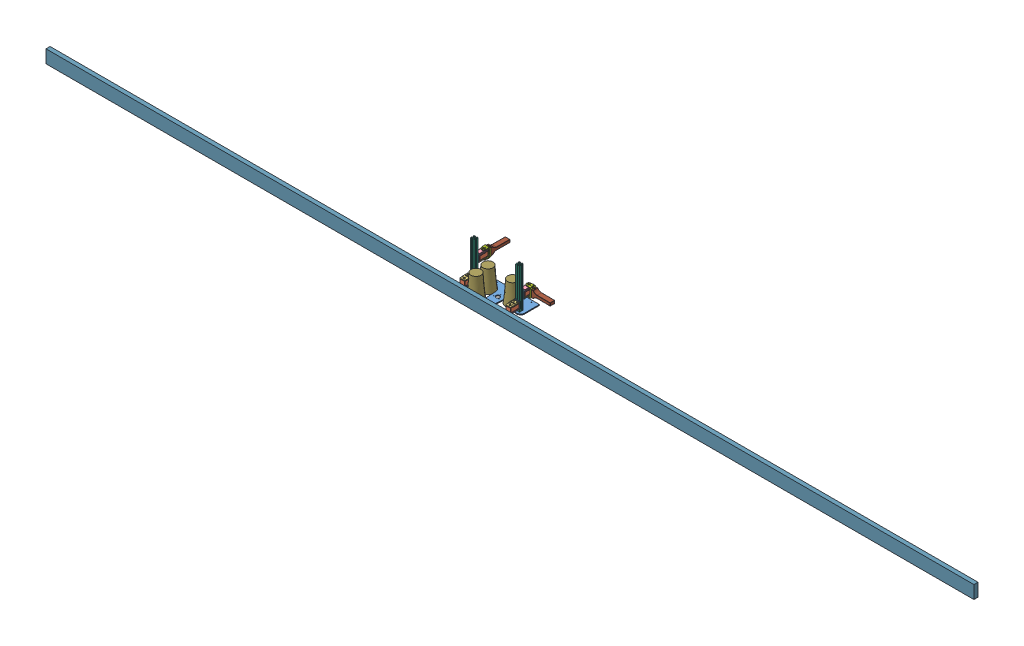
SolidWorks assembly assemblage plaque v3.0 23_12, configuration Défaut. Lengths in mm.
Overall size (5000 224.14 298.64).
45 component instances, 15 part files, 59 mates.
Components (placement in the parent):
- Plaque v1.1-1: Plaque v1.1 [Défaut] at (-264.5937 254.2279 63.4692) size (298 4.6 145)
- assemblage AX-12A avec horn F3-1: assemblage AX-12A avec horn F3 [Default] at (21.408 292.0771 45.8254) x (0.999019 0 -0.044277) z (0 1 0) size (31 53.5 38)
  - badan servo-1: badan servo [Default] at (-24.946 29.9749 -7.2009) size (25 48 22)
  - Belakang-1: Belakang [Default] at (-24.946 29.9749 14.7991) size (31 49.5 8.5)
  - depan servo-1: depan servo [Default] at (0.054 29.9749 -7.2009) x (-1 0 0) z (0 0 -1) size (31 49.5 8.5)
  - F3-1: F3 [Default] at (-12.446 36.9749 3.7991) x (-1 0 0) z (0 0 1) size (25 9 38)
- ProfileSup-1: ProfileSup [Défaut] at (6.4063 258.8279 -0.5308) x (0.999019 0 -0.044277) z (0.044277 0 0.999019) size (20 217.4 20)
- F3-1: F3 [Default] at (7.337 295.8763 9.4378) x (-0.999019 0 0.044277) z (0 1 0) size (25 9 38)
- FP04-F2-1: FP04-F2 [Default] at (5.3068 329.3416 -52.5331) x (0 1 0) z (0.999979 0 0.00642) size (48.81 25 37)
- F3-2: F3 [Default] at (7.1664 330.3416 -10.5743) x (-0.999019 0 0.044277) z (0 -1 0) size (25 9 38)
- assemblage AX-12A avec horn F3-2: assemblage AX-12A avec horn F3 [Default] at (17.9631 334.1408 -48.064) x (0.999019 0 -0.044277) z (0 -1 0) size (31 53.5 38)
  - badan servo-1: badan servo [Default] at (-24.946 29.9749 -7.2009) size (25 48 22)
  - Belakang-1: Belakang [Default] at (-24.946 29.9749 14.7991) size (31 49.5 8.5)
  - depan servo-1: depan servo [Default] at (0.054 29.9749 -7.2009) x (-1 0 0) z (0 0 -1) size (31 49.5 8.5)
  - F3-1: F3 [Default] at (-12.446 36.9749 3.7991) x (-1 0 0) z (0 0 1) size (25 9 38)
- horn-1: horn [Default] at (5.3068 346.3416 -52.5331) x (-0.999979 0 -0.00642) z (0.00642 0 -0.999979) size (20.6 4 20.6)
- horn-2: horn [Default] at (9.1967 279.8763 51.3966) x (-0.940361 0 -0.340179) z (-0.340179 0 0.940361) size (20.6 4 20.6)
- FR04-BU-1: FR04-BU [Default] at (5.3068 310.9416 -52.5331) x (1 0 0) z (0 0 -1) size (10 7.1 10)
- FR04-WA-1: FR04-WA [Default] at (5.3068 310.4416 -52.5331) x (0.9995 0 0.031614) z (-0.031614 0 0.9995) size (12 1.9 12)
- baguette v3.0 23_12-1: baguette v3.0 23_12 [Défaut] at (41.306 310.3416 -52.302) x (0.00642 0 -0.999979) z (0.999979 0 0.00642) size (25 38 102)
- ProfileSup-2: ProfileSup [Défaut] at (-237.5937 258.8279 -0.5308) size (20 217.4 20)
- AX12_F3-1: AX12_F3 [Défaut] at (-319.3447 268.4285 33.1229) x (1 0 0) z (0 1 0) size (31 53.5 38)
  - assemblage AX-12A avec horn F3-1: assemblage AX-12A avec horn F3 [Default] at (94.197 -13.3212 25.6002) size (31 53.5 38)
    - badan servo-1: badan servo [Default] at (-24.946 29.9749 -7.2009) size (25 48 22)
    - Belakang-1: Belakang [Default] at (-24.946 29.9749 14.7991) size (31 49.5 8.5)
    - depan servo-1: depan servo [Default] at (0.054 29.9749 -7.2009) x (-1 0 0) z (0 0 -1) size (31 49.5 8.5)
    - F3-1: F3 [Default] at (-12.446 36.9749 3.7991) x (-1 0 0) z (0 0 1) size (25 9 38)
  - F3-1: F3 [Default] at (81.751 23.6537 29.3994) x (-1 0 0) z (0 0 1) size (25 9 38)
- horn-3: horn [Default] at (-237.5937 281.8279 51.4692) x (0.00254 0 0.999997) z (0.999997 0 -0.00254) size (20.6 4 20.6)
- AX12_F3-2: AX12_F3 [Défaut] at (-319.3447 407.2273 -34.1845) x (1 0 0) z (0 -1 0) size (31 53.5 38)
  - assemblage AX-12A avec horn F3-1: assemblage AX-12A avec horn F3 [Default] at (94.197 -13.3212 25.6002) size (31 53.5 38)
    - badan servo-1: badan servo [Default] at (-24.946 29.9749 -7.2009) size (25 48 22)
    - Belakang-1: Belakang [Default] at (-24.946 29.9749 14.7991) size (31 49.5 8.5)
    - depan servo-1: depan servo [Default] at (0.054 29.9749 -7.2009) x (-1 0 0) z (0 0 -1) size (31 49.5 8.5)
    - F3-1: F3 [Default] at (-12.446 36.9749 3.7991) x (-1 0 0) z (0 0 1) size (25 9 38)
  - F3-1: F3 [Default] at (81.751 23.6537 29.3994) x (-1 0 0) z (0 0 1) size (25 9 38)
- horn-4: horn [Default] at (-237.5937 393.8279 -52.5308) x (0.00418 0 -0.999991) z (0.999991 0 0.00418) size (20.6 4 20.6)
- FP04-F2-2: FP04-F2 [Default] at (-237.5937 376.8279 -52.5308) x (0 -1 0) z (0.00418 0 -0.999991) size (48.81 25 37)
- baguette v3.0 23_12-2: baguette v3.0 23_12 [Défaut] at (-237.4432 357.8279 -88.5305) x (-0.999991 0 -0.00418) z (0.00418 0 -0.999991) size (25 38 102)
- Goblet_moche-1: Goblet_moche [Défaut] at (-181.3106 254.2279 -18.5717) x (0.923103 0 -0.384552) z (0 1 0) size (85.92 80.5 113.85)
- Goblet_moche-2: Goblet_moche [Défaut] at (-50.1575 254.2279 -20.3567) x (1 0 0) z (0 1 0) size (85.92 80.5 113.85)
- Goblet_moche-3: Goblet_moche [Défaut] at (-173.7307 258.8279 53.3751) x (0.805273 0 -0.592904) z (0 1 0) size (85.92 80.5 113.85)
- GrappinGauche VLED - v3.0 23_12-1: GrappinGauche VLED - v3.0 23_12 [Défaut] at (9.1967 286.8763 51.3966) x (-0.940361 0 -0.340179) z (0 -1 0) size (30.38 51.24 11)
- bordureTable_moche-1: bordureTable_moche [Défaut] at (2573.9862 322.0883 96.0579) x (0 -1 0) z (-1 0 0) size (70 22 5000)
- Flipper bras v1.0-1: Flipper bras v1.0 [Défaut] at (-237.5937 277.8279 51.4692) x (-0.999997 0 0.00254) z (0 -1 0) size (24 54.53 11)
Mates (geometry in assembly coordinates):
- Coïncidente1: coincident: circle of Plaque v1.1-1; circle of ProfileSup-1
- Coïncidente2: coincident: plane of ProfileSup-1 through (16.8393 508.8279 9.0166) normal (0.044277 0 0.999019); plane of F3-1 through (20.3243 313.5563 8.8622) normal (-0.044277 0 -0.999019)
- Coïncidente3: coincident: plane of assemblage AX-12A avec horn F3-1/Belakang-1 through (-3.7975 311.8763 17.9391) normal (0 1 0); plane of F3-1 through (-5.3737 311.8763 13.905) normal (0 -1 0)
- Coaxiale3: concentric: cylinder of assemblage AX-12A avec horn F3-1/Belakang-1 through (-0.4116 306.8763 15.2866) axis (0 1 0) radius 1; cylinder of F3-1 through (-0.4116 311.8763 15.2866) axis (0 1 0) radius 1.05
- Coaxiale4: concentric: circle of assemblage AX-12A avec horn F3-1/Belakang-1; cylinder of F3-1 through (15.5727 311.8763 14.5782) axis (0 1 0) radius 1.05
- Coïncidente5: coincident: plane of ProfileSup-1 through (-3.1411 508.8279 9.9022) normal (0.044277 0 0.999019); line of F3-1 through (3.8405 312.8763 9.5928) axis (-0.999019 0 0.044277)
- Parallèle1: parallel: line of ProfileSup-1 through (-3.1411 476.2279 9.9022) axis (0 -1 0); line of F3-1 through (-5.1507 312.8763 9.9912) axis (0 -1 0)
- Coaxiale9: concentric: cylinder of F3-2 through (14.9151 314.3416 -16.4231) axis (0 -1 0) radius 1.05; cylinder of assemblage AX-12A avec horn F3-2/Belakang-1 through (14.9151 319.3416 -16.4231) axis (0 -1 0) radius 1
- Distance4: distance = 0 mm: plane of assemblage AX-12A avec horn F3-2/Belakang-1 through (-4.6765 314.3416 -18.0573) normal (0 -1 0); plane of F3-2 through (-5.8896 314.3416 -13.8995) normal (0 1 0)
- Coaxiale10: concentric: cylinder of F3-2 through (-1.0693 314.3416 -15.7147) axis (0 -1 0) radius 1.05; cylinder of assemblage AX-12A avec horn F3-2/Belakang-1 through (-1.0693 319.3416 -15.7147) axis (0 -1 0) radius 1
- Coïncidente7: coincident: plane of ProfileSup-1 through (-4.0266 508.8279 -10.0782) normal (-0.044277 0 -0.999019); plane of F3-2 through (20.1537 312.6616 -11.1499) normal (0.044277 0 0.999019)
- Parallèle2: parallel: line of ProfileSup-1 through (-4.0266 476.2279 -10.0782) axis (0 -1 0); line of F3-2 through (-5.3213 313.3416 -10.0208) axis (0 1 0)
- Coaxiale21: concentric: cylinder of assemblage AX-12A avec horn F3-2/depan servo-1 through (5.3068 348.3416 -52.5331) axis (0 -1 0) radius 2; cylinder of horn-1 through (5.3068 350.3416 -52.5331) axis (0 -1 0) radius 2
- Distance7: distance = 0 mm: plane of horn-1 through (5.3068 346.3416 -52.5331) normal (0 -1 0); plane of assemblage AX-12A avec horn F3-2/depan servo-1 through (18.3009 346.3416 -19.0756) normal (0 1 0)
- Coaxiale22: concentric: cylinder of FP04-F2-1 through (-2.6931 305.3416 -52.5845) axis (0 -1 0) radius 1.05; cylinder of horn-1 through (-2.6931 346.3416 -52.5845) axis (0 1 0) radius 1
- Coaxiale23: concentric: cylinder of FP04-F2-1 through (5.2554 305.3416 -44.5333) axis (0 -1 0) radius 1.05; cylinder of horn-1 through (5.2554 346.3416 -44.5333) axis (0 1 0) radius 1
- Distance8: distance = 0 mm: plane of FP04-F2-1 through (5.3068 350.3416 -52.5331) normal (0 -1 0); plane of horn-1 through (5.3068 350.3416 -52.5331) normal (0 1 0)
- Coaxiale24: concentric: cylinder of assemblage AX-12A avec horn F3-1/depan servo-1 through (9.1967 277.8763 51.3966) axis (0 1 0) radius 2; cylinder of horn-2 through (9.1967 275.8763 51.3966) axis (0 1 0) radius 2
- Distance9: distance = 0 mm: plane of horn-2 through (9.1967 279.8763 51.3966) normal (0 1 0); plane of assemblage AX-12A avec horn F3-1/depan servo-1 through (19.18 279.8763 16.9208) normal (0 -1 0)
- Coaxiale27: concentric: cylinder of FP04-F2-1 through (5.3068 353.3416 -52.5331) axis (0 1 0) radius 4; cylinder of FR04-BU-1 through (5.3068 310.9416 -52.5331) axis (0 -1 0) radius 4
- Distance11: distance = 0 mm: plane of FP04-F2-1 through (5.3068 305.3416 -52.5331) normal (0 -1 0); plane of FR04-BU-1 through (0.1032 305.3416 -57.7331) normal (0 1 0)
- Coaxiale28: concentric: cylinder of FR04-BU-1 through (5.3068 310.9416 -52.5331) axis (0 -1 0) radius 4; cylinder of FR04-WA-1 through (5.3068 310.4416 -52.5331) axis (0 1 0) radius 4.025
- Distance12: distance = 0 mm: plane of FR04-WA-1 through (-1.1274 312.3416 -46.4935) normal (0 1 0); plane of assemblage AX-12A avec horn F3-2/Belakang-1 through (5.3068 312.3416 -52.5331) normal (0 -1 0)
- Coïncidente8: coincident: plane of FP04-F2-1 through (31.226 305.3416 -39.8664) normal (0.999979 0 0.00642); plane of baguette v3.0 23_12-1 through (31.242 560.3416 -42.3664) normal (-0.999979 0 -0.00642)
- Coïncidente9: coincident: line of FP04-F2-1 through (31.3865 310.3416 -64.8659) axis (0 1 0); line of baguette v3.0 23_12-1 through (31.3865 347.3416 -64.8659) axis (0 -1 0)
- Coïncidente10: coincident: line of FP04-F2-1 through (31.2741 348.3416 -47.3663) axis (-0.00642 0 0.999979); line of baguette v3.0 23_12-1 through (31.287 348.3416 -49.3662) axis (-0.00642 0 0.999979)
- Coaxiale29: concentric: circle of Plaque v1.1-1; circle of ProfileSup-2
- Parallèle3: parallel: line of Plaque v1.1-1 through (33.4063 258.8279 -81.5308) axis (-1 0 0); line of ProfileSup-2 through (-227.5937 508.8279 -10.5308) axis (-1 0 0)
- Coïncidente16: coincident: plane of Plaque v1.1-1 through (-264.5937 258.8279 63.4692) normal (0 1 0); plane of ProfileSup-2 through (-237.5937 258.8279 -0.5308) normal (0 -1 0)
- Coïncidente17: coincident: line of ProfileSup-2 through (-234.5937 476.2279 9.4692) axis (0 -1 0); line of ? through (-234.5937 302.7779 9.4692) axis (0 -1 0)
- Parallèle7: parallel: plane of ProfileSup-2 through (-247.5937 508.8279 9.4692) normal (0 0 1); line of ? through (-250.0937 316.8279 11.4692) axis (1 0 0)
- Coaxiale30: concentric: cylinder of AX12_F3-1/assemblage AX-12A avec horn F3-1/depan servo-1 through (-237.5937 279.8279 51.4692) axis (0 1 0) radius 2; cylinder of horn-3 through (-237.5937 277.8279 51.4692) axis (0 1 0) radius 2
- Distance13: distance = 20 mm: line of ? through (-241.0937 278.8279 11.4692) axis (-1 0 0); plane of Plaque v1.1-1 through (-264.5937 258.8279 63.4692) normal (0 1 0)
- Coïncidente19: coincident: plane of AX12_F3-1/assemblage AX-12A avec horn F3-1/depan servo-1 through (-226.0937 281.8279 17.4692) normal (0 -1 0); plane of horn-3 through (-237.5937 281.8279 51.4692) normal (0 1 0)
- Coïncidente20: coincident: line of ProfileSup-2 through (-234.5937 476.2279 -10.5308) axis (0 -1 0); line of ? through (-234.5937 380.4736 -10.5308) axis (0 1 0)
- Parallèle9: parallel: plane of ProfileSup-2 through (-247.5937 508.8279 -10.5308) normal (0 0 -1); line of ? through (-241.0937 396.8279 -12.5308) axis (-1 0 0)
- Coaxiale31: concentric: cylinder of AX12_F3-2/assemblage AX-12A avec horn F3-1/depan servo-1 through (-237.5937 395.8279 -52.5308) axis (0 -1 0) radius 2; cylinder of horn-4 through (-237.5937 397.8279 -52.5308) axis (0 -1 0) radius 2
- Coïncidente21: coincident: plane of AX12_F3-2/assemblage AX-12A avec horn F3-1/depan servo-1 through (-226.0937 393.8279 -18.5308) normal (0 1 0); plane of horn-4 through (-237.5937 393.8279 -52.5308) normal (0 -1 0)
- Distance14: distance = 100 mm: line of ? through (-250.0937 358.8279 -12.5308) axis (1 0 0); plane of Plaque v1.1-1 through (-264.5937 258.8279 63.4692) normal (0 1 0)
- Coaxiale32: concentric: circle of horn-4; circle of FP04-F2-2
- Coaxiale33: concentric: circle of horn-4; circle of FP04-F2-2
- Coïncidente22: coincident: plane of horn-4 through (-237.5937 397.8279 -52.5308) normal (0 1 0); plane of FP04-F2-2 through (-237.5937 397.8279 -52.5308) normal (0 -1 0)
- Coïncidente23: coincident: line of FP04-F2-2 through (-240.485 381.2779 -78.5431) axis (0 -1 0); line of baguette v3.0 23_12-2 through (-240.485 395.8279 -78.5431) axis (0 -1 0)
- Coïncidente24: coincident: plane of FP04-F2-2 through (-249.9849 400.8279 -78.5828) normal (0.00418 0 -0.999991); plane of baguette v3.0 23_12-2 through (-227.4851 607.8279 -78.4888) normal (-0.00418 0 0.999991)
- Coïncidente25: coincident: line of FP04-F2-2 through (-232.485 395.8279 -78.5097) axis (0.999991 0 0.00418); line of baguette v3.0 23_12-2 through (-234.485 395.8279 -78.518) axis (0.999991 0 0.00418)
- Tangent1: tangent: circle of Plaque v1.1-1; circle of Goblet_moche-1
- Parallèle10: parallel: plane of Plaque v1.1-1 through (-264.5937 258.8279 63.4692) normal (0 1 0); plane of Goblet_moche-1 through (-181.3106 368.0779 -18.5717) normal (0 1 0)
- Parallèle11: parallel: plane of Plaque v1.1-1 through (-264.5937 258.8279 63.4692) normal (0 1 0); plane of Goblet_moche-2 through (-50.1575 368.0779 -20.3567) normal (0 1 0)
- Tangent2: tangent: circle of Plaque v1.1-1; circle of Goblet_moche-2
- Parallèle12: parallel: plane of Plaque v1.1-1 through (-264.5937 258.8279 63.4692) normal (0 1 0); plane of Goblet_moche-3 through (-173.7307 372.6779 53.3751) normal (0 1 0)
- Coaxiale35: concentric: circle of horn-2; circle of GrappinGauche VLED - v3.0 23_12-1
- Coaxiale36: concentric: circle of horn-2; circle of GrappinGauche VLED - v3.0 23_12-1
- Coïncidente27: coincident: plane of horn-2 through (9.1967 275.8763 51.3966) normal (0 -1 0); plane of GrappinGauche VLED - v3.0 23_12-1 through (9.1967 275.8763 51.3966) normal (0 1 0)
- Parallèle13: parallel: plane of Plaque v1.1-1 through (-264.5937 258.8279 63.4692) normal (0 1 0); plane of bordureTable_moche-1 through (-2426.0138 322.0883 96.0579) normal (0 1 0)
- Parallèle17: parallel: line of Plaque v1.1-1 through (33.4063 258.8279 -81.5308) axis (-1 0 0); line of bordureTable_moche-1 through (-2426.0138 252.0883 96.0579) axis (1 0 0)
- Tangent3: tangent: circle of Plaque v1.1-1; circle of Goblet_moche-3
- Coaxiale37: concentric: circle of horn-3; circle of Flipper bras v1.0-1
- Coaxiale38: concentric: circle of horn-3; circle of Flipper bras v1.0-1
- Coïncidente28: coincident: plane of horn-3 through (-237.5937 277.8279 51.4692) normal (0 -1 0); plane of Flipper bras v1.0-1 through (-237.5021 277.8279 87.4976) normal (0 1 0)
